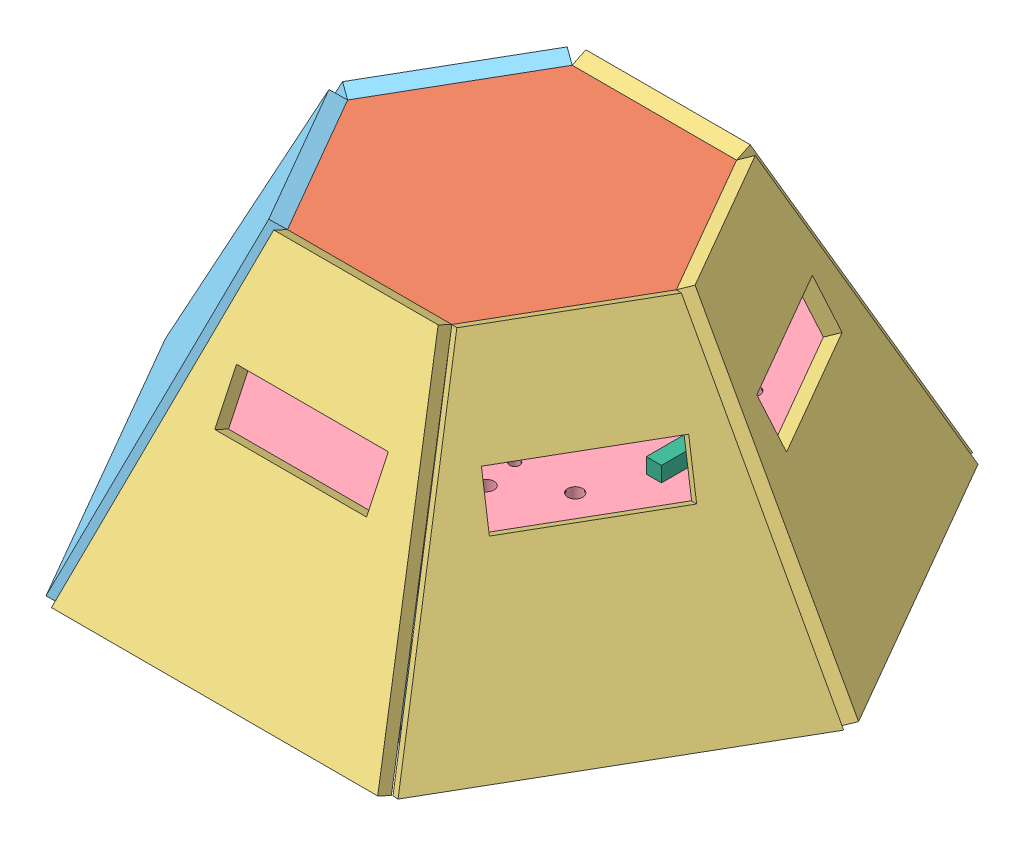
SolidWorks assembly Ensamblaje2, configuration Predeterminado. Lengths in mm.
Overall size (134.1 59.97 117.61).
13 component instances, 6 part files, 43 mates.
Components (placement in the parent):
- BASE NUEVO-1: BASE NUEVO [Predeterminado] at (-4.2838 -17.1747 120) size (120 3 103.92)
- PLACA SUPERIOR NUEVO-1: PLACA SUPERIOR NUEVO [Predeterminado] at (-4.2838 32.8253 120) size (65 3 56.29)
- CARA-1: CARA [Predeterminado] at (27.5395 17.7689 138.3732) x (0.781863 0.430024 0.451409) z (-0.5 0 0.866025) size (3 65 64.5)
- CARA-2: CARA [Predeterminado] at (-4.2838 19.059 159.4548) x (0 -0.430024 -0.902817) z (1 0 0) size (3 65 64.5)
- CARA-3: CARA [Predeterminado] at (27.5395 17.7689 101.6268) x (0.781863 0.430024 -0.451409) z (0.5 0 0.866025) size (3 65 64.5)
- PLANCHA-1: PLANCHA [Predeterminado] at (-4.2838 5.5526 120) size (95 3 82.27)
- CARA-5: CARA [Predeterminado] at (-4.2838 19.059 80.5452) x (0 -0.430024 0.902817) z (-1 0 0) size (3 65 64.5)
- TAPA SIN SENSOR-1: TAPA SIN SENSOR [Predeterminado] at (-44.0293 6.9267 98.3741) x (0.781863 -0.430024 0.451409) z (-0.5 0 0.866025) size (3 65 64.5)
- TAPA SIN SENSOR-2: TAPA SIN SENSOR [Predeterminado] at (-42.8851 6.9267 143.6077) x (0.781863 -0.430024 -0.451409) z (0.5 0 0.866025) size (3 65 64.5)
- TOPES-1: TOPES [Predeterminado] at (-5.4614 5.5526 138.2765) size (16 6 3)
- TOPES-2: TOPES [Predeterminado] at (31.0386 5.5526 119.2765) x (0 0 -1) z (1 0 0) size (16 6 3)
- TOPES-3: TOPES [Predeterminado] at (-5.4614 5.5526 100.2765) size (16 6 3)
- TOPES-4: TOPES [Predeterminado] at (-41.9614 5.5526 119.2765) x (0 0 -1) z (1 0 0) size (16 6 3)
Mates (geometry in assembly coordinates):
- Paralelo1: parallel: plane of BASE NUEVO-1 through (-34.2838 -14.1747 171.9615) normal (0 0 1); plane of PLACA SUPERIOR NUEVO-1 through (-20.5338 35.8253 148.1458) normal (0 0 1)
- Paralelo2: parallel: plane of BASE NUEVO-1 through (25.7162 -14.1747 171.9615) normal (0.866025 0 0.5); plane of PLACA SUPERIOR NUEVO-1 through (11.9662 35.8253 148.1458) normal (0.866025 0 0.5)
- Paralelo3: parallel: plane of BASE NUEVO-1 through (55.7162 -14.1747 120) normal (0.866025 0 -0.5); plane of PLACA SUPERIOR NUEVO-1 through (28.2162 35.8253 120) normal (0.866025 0 -0.5)
- Paralelo4: parallel: plane of BASE NUEVO-1 through (25.7162 -14.1747 68.0385) normal (0 0 -1); plane of PLACA SUPERIOR NUEVO-1 through (11.9662 35.8253 91.8542) normal (0 0 -1)
- Paralelo5: parallel: plane of BASE NUEVO-1 through (-4.2838 -14.1747 120) normal (0 1 0); plane of PLACA SUPERIOR NUEVO-1 through (-4.2838 32.8253 120) normal (0 -1 0)
- Coincidente8: coincident: line of PLACA SUPERIOR NUEVO-1 through (11.9662 35.8253 148.1458) axis (0.5 0 -0.866025); plane of CARA-1 through (27.5395 17.7689 138.3732) normal (-0.781863 -0.430024 -0.451409)
- Coincidente9: coincident: line of BASE NUEVO-1 through (25.7162 -14.1747 171.9615) axis (0.5 0 -0.866025); plane of CARA-1 through (27.5395 17.7689 138.3732) normal (-0.781863 -0.430024 -0.451409)
- Coincidente12: coincident: line of PLACA SUPERIOR NUEVO-1 through (11.9662 35.8253 148.1458) axis (0.5 0 -0.866025); line of CARA-1 through (28.2162 35.8253 120) axis (-0.5 0 0.866025)
- Coincidente15: coincident: plane of BASE NUEVO-1 through (-4.2838 -17.1747 120) normal (0 0 1); plane of PLACA SUPERIOR NUEVO-1 through (-4.2838 32.8253 120) normal (0 0 1)
- Coincidente16: coincident: plane of BASE NUEVO-1 through (-4.2838 -17.1747 120) normal (1 0 0); plane of PLACA SUPERIOR NUEVO-1 through (-4.2838 32.8253 120) normal (1 0 0)
- Coincidente17: coincident: point of PLACA SUPERIOR NUEVO-1; point of CARA-1
- Coincidente21: coincident: line of PLACA SUPERIOR NUEVO-1 through (-20.5338 35.8253 148.1458) axis (1 0 0); line of CARA-2 through (-20.5338 35.8253 148.1458) axis (1 0 0)
- Coincidente22: coincident: line of BASE NUEVO-1 through (-34.2838 -14.1747 171.9615) axis (1 0 0); plane of CARA-2 through (-4.2838 17.7689 156.7463) normal (0 -0.430024 -0.902817)
- Coincidente23: coincident: point of PLACA SUPERIOR NUEVO-1; point of CARA-2
- Coincidente24: coincident: line of BASE NUEVO-1 through (55.7162 -14.1747 120) axis (-0.5 0 -0.866025); plane of CARA-3 through (27.5395 17.7689 101.6268) normal (-0.781863 -0.430024 0.451409)
- Coincidente25: coincident: line of PLACA SUPERIOR NUEVO-1 through (28.2162 35.8253 120) axis (-0.5 0 -0.866025); line of CARA-3 through (11.9662 35.8253 91.8542) axis (0.5 0 0.866025)
- Coincidente26: coincident: point of PLACA SUPERIOR NUEVO-1; point of CARA-3
- Coincidente27: coincident: plane of CARA-3 through (27.5395 17.7689 101.6268) normal (-0.781863 -0.430024 0.451409); line of PLANCHA-1 through (43.2162 8.5526 120) axis (-0.5 0 -0.866025)
- Paralelo7: parallel: plane of BASE NUEVO-1 through (-4.2838 -14.1747 120) normal (0 1 0); plane of PLANCHA-1 through (-4.2838 5.5526 120) normal (0 -1 0)
- Coincidente29: coincident: plane of CARA-2 through (-4.2838 17.7689 156.7463) normal (0 -0.430024 -0.902817); line of PLANCHA-1 through (-28.0338 8.5526 161.1362) axis (1 0 0)
- Coincidente30: coincident: plane of CARA-1 through (27.5395 17.7689 138.3732) normal (-0.781863 -0.430024 -0.451409); line of PLANCHA-1 through (19.4662 8.5526 161.1362) axis (0.5 0 -0.866025)
- Coincidente41: coincident: line of PLACA SUPERIOR NUEVO-1 through (11.9662 35.8253 91.8542) axis (-1 0 0); line of CARA-5 through (11.9662 35.8253 91.8542) axis (-1 0 0)
- Coincidente42: coincident: line of BASE NUEVO-1 through (25.7162 -14.1747 68.0385) axis (-1 0 0); plane of CARA-5 through (-4.2838 17.7689 83.2537) normal (0 -0.430024 0.902817)
- Coincidente43: coincident: point of PLACA SUPERIOR NUEVO-1; point of CARA-5
- Coincidente51: coincident: line of BASE NUEVO-1 through (-34.2838 -14.1747 68.0385) axis (-0.5 0 0.866025); plane of TAPA SIN SENSOR-1 through (-41.6837 5.6366 99.7284) normal (0.781863 -0.430024 0.451409)
- Coincidente54: coincident: line of BASE NUEVO-1 through (-64.2838 -14.1747 120) axis (0.5 0 0.866025); plane of TAPA SIN SENSOR-2 through (-40.5395 5.6366 142.2535) normal (0.781863 -0.430024 -0.451409)
- Distancia3: distance = 50 mm: plane of BASE NUEVO-1 through (-4.2838 -14.1747 120) normal (0 1 0); plane of PLACA SUPERIOR NUEVO-1 through (-4.2838 35.8253 120) normal (0 1 0)
- Coincidente58: coincident: line of PLACA SUPERIOR NUEVO-1 through (-20.5338 35.8253 91.8542) axis (-0.5 0 0.866025); line of TAPA SIN SENSOR-1 through (-20.5338 35.8253 91.8542) axis (-0.5 0 0.866025)
- Coincidente59: coincident: point of CARA-5; point of TAPA SIN SENSOR-1
- Coincidente60: coincident: line of PLACA SUPERIOR NUEVO-1 through (-36.7838 35.8253 120) axis (0.5 0 0.866025); line of TAPA SIN SENSOR-2 through (-36.7838 35.8253 120) axis (0.5 0 0.866025)
- Coincidente61: coincident: point of TAPA SIN SENSOR-1; point of TAPA SIN SENSOR-2
- Coincidente62: coincident: plane of PLANCHA-1 through (-10.4614 5.5526 139.7765) normal (0 0 -1); plane of TOPES-1 through (-0.4614 8.5526 139.7765) normal (0 0 1)
- Coincidente63: coincident: plane of PLANCHA-1 through (-4.2838 8.5526 120) normal (0 1 0); plane of TOPES-1 through (-5.4614 8.5526 138.2765) normal (0 -1 0)
- Coincidente64: coincident: plane of PLANCHA-1 through (-0.4614 5.5526 139.7765) normal (-1 0 0); plane of TOPES-1 through (-0.4614 8.5526 139.7765) normal (1 0 0)
- Coincidente65: coincident: plane of PLANCHA-1 through (32.5386 5.5526 114.2765) normal (-1 0 0); plane of TOPES-2 through (32.5386 8.5526 114.2765) normal (1 0 0)
- Coincidente66: coincident: plane of PLANCHA-1 through (29.5386 5.5526 114.2765) normal (0 0 1); plane of TOPES-2 through (32.5386 8.5526 114.2765) normal (0 0 -1)
- Coincidente67: coincident: plane of PLANCHA-1 through (-4.2838 8.5526 120) normal (0 1 0); plane of TOPES-2 through (31.0386 8.5526 119.2765) normal (0 -1 0)
- Coincidente69: coincident: plane of PLANCHA-1 through (-0.4614 5.5526 98.7765) normal (-1 0 0); plane of TOPES-3 through (-0.4614 8.5526 101.7765) normal (1 0 0)
- Coincidente70: coincident: plane of PLANCHA-1 through (-4.2838 8.5526 120) normal (0 1 0); plane of TOPES-3 through (-5.4614 8.5526 100.2765) normal (0 -1 0)
- Coincidente71: coincident: plane of PLANCHA-1 through (-0.4614 5.5526 101.7765) normal (0 0 -1); plane of TOPES-3 through (-0.4614 8.5526 101.7765) normal (0 0 1)
- Coincidente72: coincident: plane of PLANCHA-1 through (-43.4614 5.5526 114.2765) normal (1 0 0); plane of TOPES-4 through (-43.4614 8.5526 114.2765) normal (-1 0 0)
- Coincidente73: coincident: plane of PLANCHA-1 through (-40.4614 5.5526 114.2765) normal (0 0 1); plane of TOPES-4 through (-40.4614 8.5526 114.2765) normal (0 0 -1)
- Coincidente74: coincident: plane of PLANCHA-1 through (-4.2838 8.5526 120) normal (0 1 0); plane of TOPES-4 through (-41.9614 8.5526 119.2765) normal (0 -1 0)
